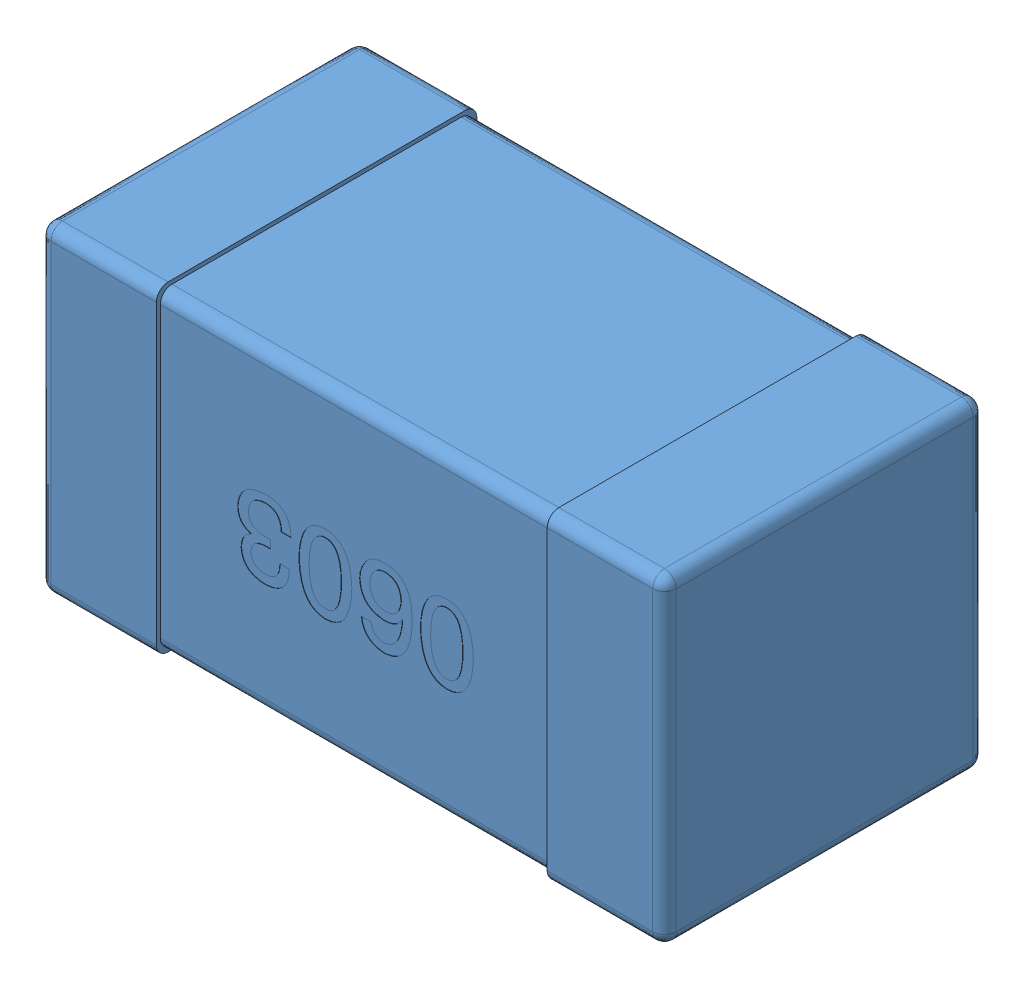
SolidWorks assembly 0603电容, configuration 默认. Lengths in mm.
Overall size (1.6 0.82 0.82).
2 component instances, 1 part files, 0 mates.
Components (placement in the parent):
- C_0603^0603电容-1: C_0603^0603电容 [默认] at (34.005 43.815 0) x (-1 0 0) z (0 0 1) size (1.6 0.82 0.82) (virtual)
  - C_0603-9^C_0603_0603电容-1: C_0603-9^C_0603_0603电容 [默认] at origin size (1.6 0.82 0.82) (virtual)
